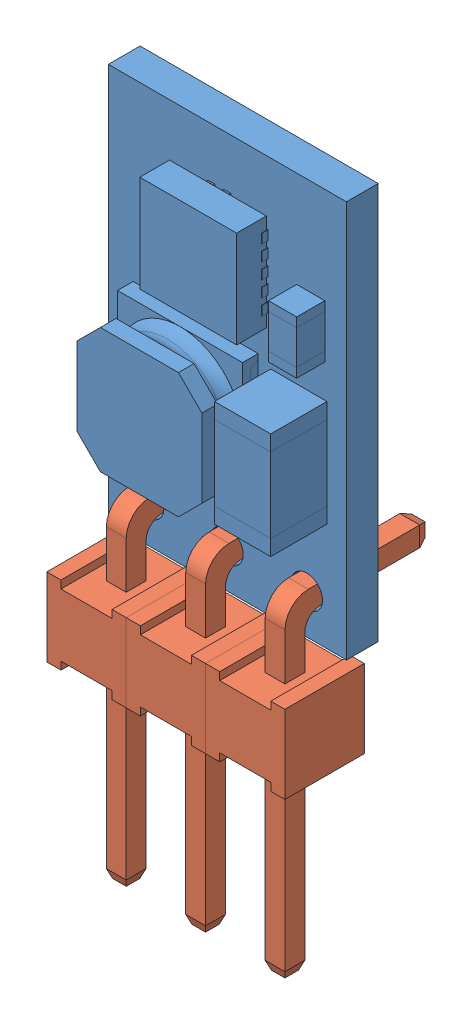
SolidWorks assembly d45v1e1fx-step-down-voltage-regulators_with_header, configuration Default. Lengths in mm.
Overall size (8.38 21.58 5.92).
2 component instances, 2 part files, 7 mates.
Components (placement in the parent):
- d45v1e1fx-step-down-voltage-regulators.step-1: d45v1e1fx-step-down-voltage-regulators.step [Default] at (-3.81 2.881 0) size (7.62 12.7 4.19)
- Right angle pin header_03.step-1: Right angle pin header_03.step [Default] at (3.81 4.5 -2.5555) x (-1 0 0) z (0 1 0) size (7.62 5.54 10.5)
Mates (geometry in assembly coordinates):
- Symmetric1: symmetric aligned: plane of d45v1e1fx-step-down-voltage-regulators.step-1 through (-3.81 15.581 1.016) normal (-1 0 0); plane of d45v1e1fx-step-down-voltage-regulators.step-1 through (3.81 2.881 1.016) normal (1 0 0)
- Parallel1: parallel aligned: plane of d45v1e1fx-step-down-voltage-regulators.step-1 through (3.81 15.581 1.016) normal (0 1 0)
- Coincident1: coincident anti-aligned: plane of d45v1e1fx-step-down-voltage-regulators.step-1 through (-3.81 2.881 0) normal (0 0 -1)
- Distance2: distance = 0.381 mm anti-aligned: plane of d45v1e1fx-step-down-voltage-regulators.step-1 through (-3.81 2.881 1.016) normal (0 0 1); plane of Right angle pin header_03.step-1 through (-2.2225 -17.398 1.397) normal (0 0 -1)
- Distance1: distance = 0.381 mm anti-aligned: plane of Right angle pin header_03.step-1 through (-1.27 2.5 -2.5555) normal (0 1 0); plane of d45v1e1fx-step-down-voltage-regulators.step-1 through (-3.81 2.881 1.016) normal (0 -1 0)
- Coincident4: coincident anti-aligned: plane of Right angle pin header_03.step-1 through (-1.27 0 -2.5555) normal (0 -1 0)
- Symmetric2: symmetric aligned: plane of Right angle pin header_03.step-1 through (-3.81 0.25 2.9845) normal (-1 0 0); plane of Right angle pin header_03.step-1 through (3.81 0.25 2.9845) normal (1 0 0)
